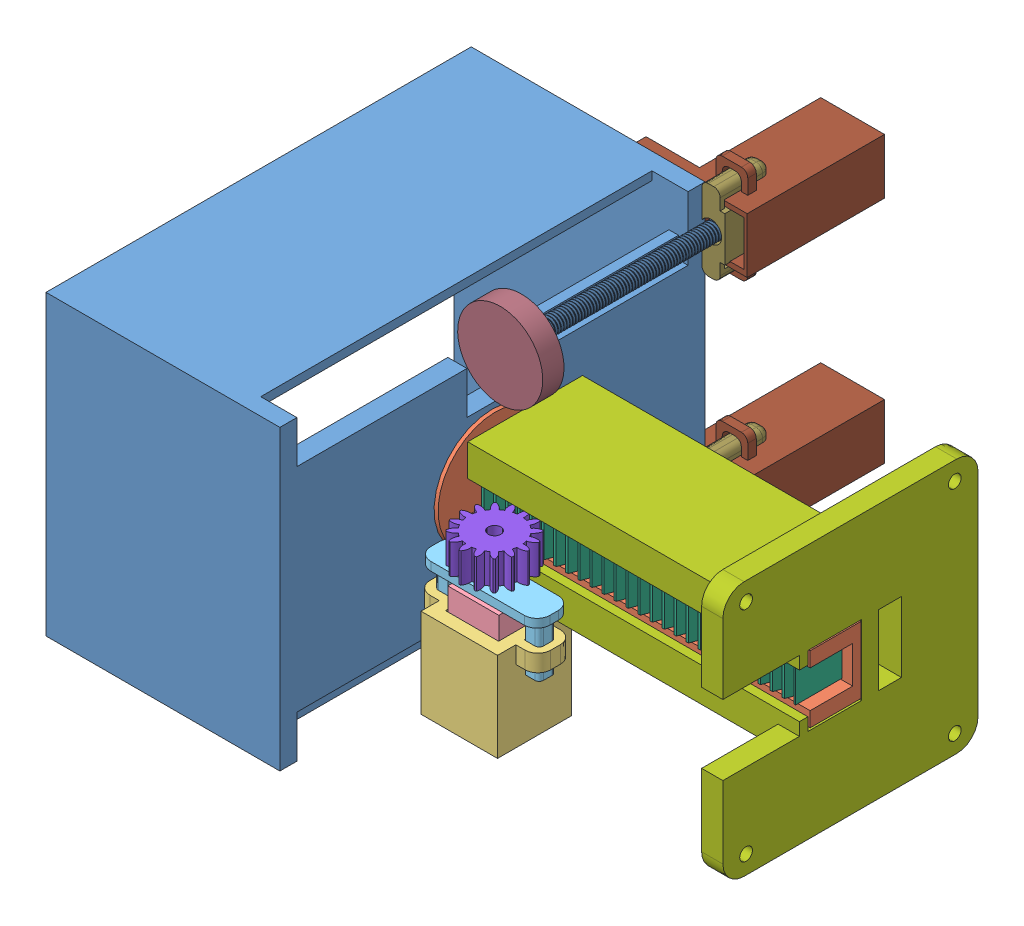
SolidWorks assembly Elevator assembly, configuration Default. Lengths in mm.
Overall size (135.78 136.98 142.22).
22 component instances, 13 part files, 6 mates.
Components (placement in the parent):
- 1-1: 1 [Default] at (53.0834 92.1657 82.0505) size (135.78 70 100)
  - Poker case v3-1: Poker case v3 [Default] at (30.0227 66.0033 141.0318) x (0 -1 0) z (-1 0 0) size (70 100 55)
  - rack platform V3-1: rack platform V3 [Default] at (70.7227 66.0033 135.0318) x (0 1 0) z (1 0 0) size (27 27 84.5)
  - motor new assembly-1: motor new assembly [Default] at (57.6092 76.4665 204.2094) x (-1 0 0) z (0 -1 0) size (28.4 40.99 35)
    - motor platform-1: motor platform [Default] at (-46.6208 56.5775 23.7133) x (0 -1 0) z (0 0 1) size (40.99 28.4 21)
    - motor-1: motor [Default] at (12.8082 43.8847 35.7133) x (0 0 -1) z (0 1 0) size (34 12 10)
    - motor enclosure-1: motor enclosure [Default] at (12.8082 48.8847 18.7133) x (0 1 0) z (0 0 -1) size (8 28 14)
  - rack spur rectangular_am-1: rack spur rectangular_am [Metric - Rack-spur - rectangular 0.9M 20PA 8FW 10PH 75L---SAll] at (33.2227 62.0033 137.0318) x (1 0 0) z (0 -1 0) size (75 10.9 8)
  - rack base V3-1: rack base V3 [Default] at (69.3011 52.7533 137.6318) x (0 0 -1) z (0 1 0) size (60 78 60)
  - spur gear_am-1: spur gear_am [Metric - Spur gear 0.9M 16T 20PA 7FW ---S16N75H50L3N] at (44.8011 69.5033 155.3247) x (0 -1 0) z (-0.827545 0 -0.561399) size (7 15.96 15.96)
- Motor& Roller Assembly-1: Motor& Roller Assembly [Default] at (126.5135 135.5052 205.2011) x (0.911717 -0.409751 -0.029593) z (0.152052 0.269648 0.950879) size (37.73 49.45 90.57)
  - M4 Nut-1: M4 Nut [Default] at (-57.6374 23.3149 21.5168) x (-0.029593 -0.308146 0.950879) z (-0.746697 -0.625603 -0.225974) size (3.68 8.08 7)
  - New Motor-1: New Motor [Default] at (-55.4937 47.1227 -53.1513) x (0.911717 0.381644 0.152052) z (-0.029593 -0.308146 0.950879) size (12 10.57 80.84)
  - New Motor case-1: New Motor case [Default] at (-61.8608 35.4016 -24.2309) x (0.409751 -0.871432 -0.269648) z (0.029593 0.308146 -0.950879) size (23 30 32.3)
  - New Motor enclosure-1: New Motor enclosure [Default] at (-56.5651 37.0441 -22.2718) x (0.409751 -0.871432 -0.269648) z (0.029593 0.308146 -0.950879) size (18.9 5.4 12)
  - New Motor roller-1: New Motor roller [Default] at (-57.2018 24.4066 19.3601) x (0.972856 0.20955 0.098185) z (-0.029593 -0.308146 0.950879) size (20 20 7)
- Motor& Roller Assembly-2: Motor& Roller Assembly [Default] at (126.5135 81.5052 205.2011) x (0.911717 -0.409751 -0.029593) z (0.152052 0.269648 0.950879) size (37.73 49.45 90.57)
  - M4 Nut-1: M4 Nut [Default] at (-57.6374 23.3149 21.5168) x (-0.029593 -0.308146 0.950879) z (-0.746697 -0.625603 -0.225974) size (3.68 8.08 7)
  - New Motor-1: New Motor [Default] at (-55.4937 47.1227 -53.1513) x (0.911717 0.381644 0.152052) z (-0.029593 -0.308146 0.950879) size (12 10.57 80.84)
  - New Motor case-1: New Motor case [Default] at (-61.8608 35.4016 -24.2309) x (0.409751 -0.871432 -0.269648) z (0.029593 0.308146 -0.950879) size (23 30 32.3)
  - New Motor enclosure-1: New Motor enclosure [Default] at (-56.5651 37.0441 -22.2718) x (0.409751 -0.871432 -0.269648) z (0.029593 0.308146 -0.950879) size (18.9 5.4 12)
  - New Motor roller-1: New Motor roller [Default] at (-57.2018 24.4066 19.3601) x (0.972856 0.20955 0.098185) z (-0.029593 -0.308146 0.950879) size (20 20 7)
Mates (geometry in assembly coordinates):
- Coincident1: coincident anti-aligned: plane of 1-1/Poker case v3-1 through (28.1061 123.169 173.0823) normal (0 0 -1); plane of Motor& Roller Assembly-2/New Motor case-1 through (73.1771 131.0432 173.0823) normal (0 0 1)
- Concentric2: concentric aligned: cylinder of 1-1/Poker case v3-1 through (65.7061 131.169 176.0823) axis (0 0 -1) radius 1; circle of Motor& Roller Assembly-2/New Motor case-1
- Coincident3: coincident anti-aligned: plane of 1-1/Poker case v3-1 through (28.1061 123.169 173.0823) normal (0 0 -1); plane of Motor& Roller Assembly-1/New Motor case-1 through (73.1771 185.0432 173.0823) normal (0 0 1)
- Concentric5: concentric aligned: cylinder of 1-1/Poker case v3-1 through (65.7061 185.169 176.0823) axis (0 0 -1) radius 1; cylinder of Motor& Roller Assembly-1/New Motor case-1 through (65.7061 185.169 173.0823) axis (0 0 -1) radius 1
- Parallel2: parallel aligned: plane of 1-1/Poker case v3-1 through (83.1061 158.169 223.0823) normal (1 0 0); plane of Motor& Roller Assembly-1/New Motor case-1 through (92.9977 177.1338 169.2823) normal (1 0 0)
- Parallel3: parallel aligned: plane of 1-1/Poker case v3-1 through (83.1061 158.169 223.0823) normal (1 0 0); plane of Motor& Roller Assembly-2/New Motor case-1 through (92.9977 123.1338 169.2823) normal (1 0 0)
